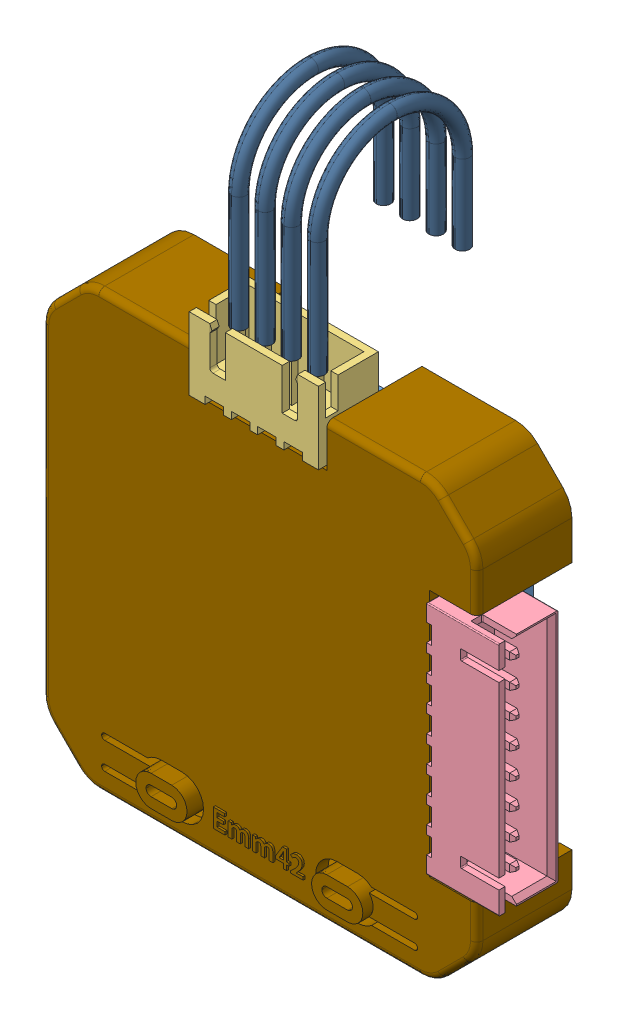
SolidWorks assembly 42步进电机, configuration 默认. Lengths in mm.
Overall size (44.65 62.9 75).
29 component instances, 11 part files, 0 mates.
Components (placement in the parent):
- ZDT_X42_L48Motor.STEP-1: ZDT_X42_L48Motor.STEP [默认] at origin size (44.65 62.9 75)
  - ZDT_X42_V1.2_PCB.step.STEP-1: ZDT_X42_V1.2_PCB.step.STEP [默认] at (-22.6099 -24.1857 75.7634) size (43.15 43.58 9.15)
    - Board.step.STEP-1: Board.step.STEP [默认] at origin size (39 39 1.76)
      - Open CASCADE STEP translator 6.8 4.1.1.step.STEP-1: Open CASCADE STEP translator 6.8 4.1.1.step.STEP [默认] at (0 0 -1.7634)
    - Next.step.STEP-1: Next.step.STEP [默认] at origin size (5.2 3.35 2.5)
      - ts-1145a-b-a_White.step.STEP-1: ts-1145a-b-a_White.step.STEP [默认] at (11 2.032 0) x (-1 0 0) z (0 1 0)
    - J6.step.STEP-1: J6.step.STEP [默认] at origin size (12.5 7.6 8.9)
      - User_Library-XH2_54-4P-AW.step.STEP-1: User_Library-XH2_54-4P-AW.step.STEP [默认] at (19.4999 36.576 2.9) x (-1 0 0) z (0 1 0)
    - J3.step.STEP-1: J3.step.STEP [默认] at origin size (7.7 22.78 9.1)
      - XH2.54-8P_H.step.STEP-1: XH2.54-8P_H.step.STEP [默认] at (35.8 10.36 0.05) x (0 1 0) z (1 0 0) size (22.78 9.1 7.7)
        - XH2.54-8P_H-0.step.STEP-1: XH2.54-8P_H-0.step.STEP [默认] at origin
    - J1.step.STEP-1: J1.step.STEP [默认] at origin size (11.94 10.55 1.5)
      - 6308926992.step.STEP-1: 6308926992.step.STEP [默认] at (19.4687 19.9339 0) size (11.94 10.55 1.4)
        - Extruded.step.STEP-1: Extruded.step.STEP [默认] at origin
      - 6308926832.step.STEP-1: 6308926832.step.STEP [默认] at (19.4687 21.0858 0) size (11.94 8.25 1.5)
        - Extruded-1.step.STEP-1: Extruded-1.step.STEP [默认] at origin
    - Enter.step.STEP-1: Enter.step.STEP [默认] at origin size (5.2 3.35 2.5)
      - ts-1145a-b-a_White.step.STEP-1: ts-1145a-b-a_White.step.STEP [默认] at (28 2.032 0) x (-1 0 0) z (0 1 0)
  - ZDT_STEPPER_MOTOR_42_L40-1: ZDT_STEPPER_MOTOR_42_L40 [默认] at (-3.1099 -4.6857 71) x (-1 0 0) z (0 0 -1)
  - SHIM_3x7x3.STEP-1: SHIM_3x7x3.STEP [默认] at (-18.6099 10.8143 71)
  - SHIM_3x7x3.STEP-2: SHIM_3x7x3.STEP [默认] at (12.3901 10.8143 71)
  - SHIM_3x7x3.STEP-3: SHIM_3x7x3.STEP [默认] at (-18.6099 -20.1857 71)
  - SHIM_3x7x3.STEP-4: SHIM_3x7x3.STEP [默认] at (12.3901 -20.1857 71)
  - M3x6mm_Phillips.STEP-1: M3x6mm_Phillips.STEP [默认] at (-18.6099 10.8143 75.7634) x (-1 0 0) z (0 0 -1)
  - M3x6mm_Phillips.STEP-2: M3x6mm_Phillips.STEP [默认] at (12.3901 10.8143 75.7634) x (-1 0 0) z (0 0 -1)
  - M3x6mm_Phillips.STEP-3: M3x6mm_Phillips.STEP [默认] at (-18.6099 -20.1857 75.7634) x (-1 0 0) z (0 0 -1)
  - M3x6mm_Phillips.STEP-4: M3x6mm_Phillips.STEP [默认] at (12.3901 -20.1857 75.7634) x (-1 0 0) z (0 0 -1)
  - ZDT_X42_V1.2.STEP-1: ZDT_X42_V1.2.STEP [默认] at (-22.6099 -24.1857 79.8)
  - WIRE_2.54.STEP-1: WIRE_2.54.STEP [默认] at (-6.9141 21.8143 65.2083) x (1 0 0) z (0 -1 0)
